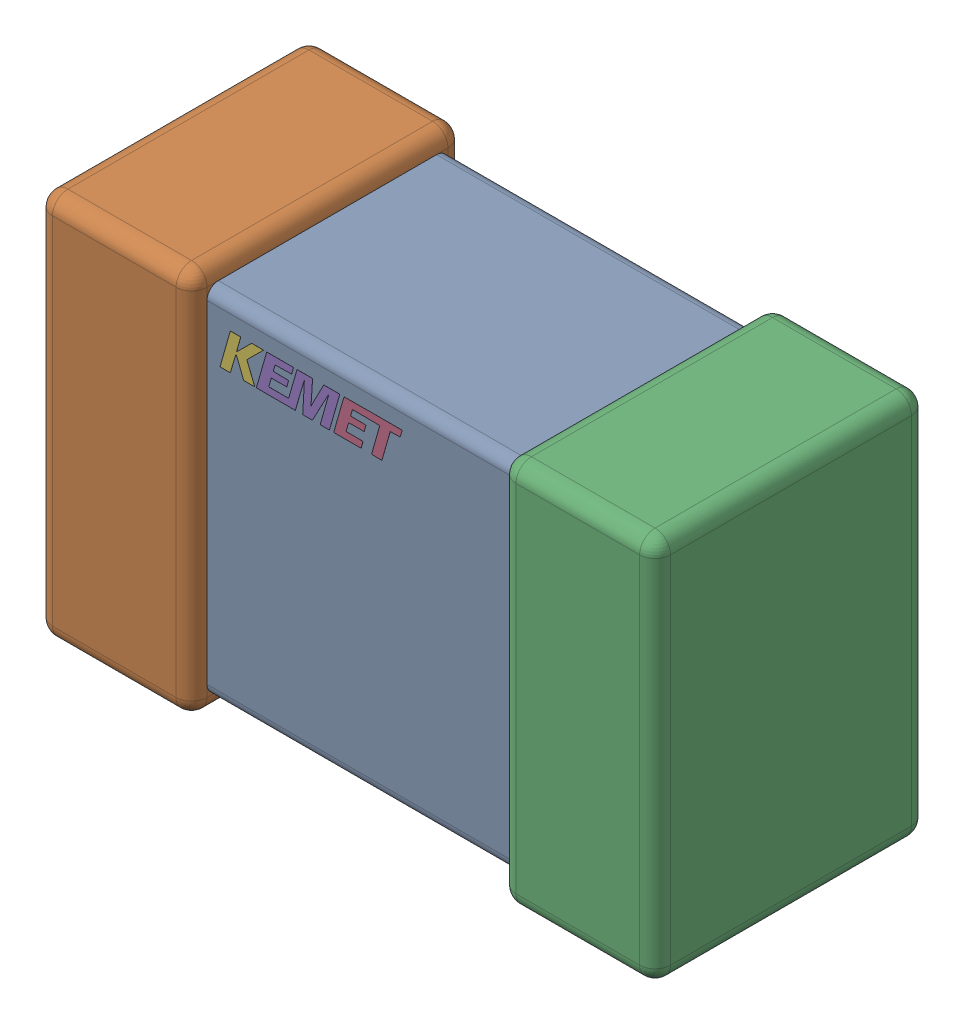
SolidWorks assembly C17.step, configuration Default. Lengths in mm.
Overall size (2 1.25 0.88).
3 component instances, 3 part files, 0 mates.
Components (placement in the parent):
- Cap_KEMET_C0805C472J3HAC_eec.step-1: Cap_KEMET_C0805C472J3HAC_eec.step [Default] at (56.841 45.974 0) size (1 1.15 0.78)
- Cap_KEMET_C0805C472J3HAC_eec-7.step-1: Cap_KEMET_C0805C472J3HAC_eec-7.step [Default] at (56.841 45.974 0) size (2 1.25 0.88)
- Cap_KEMET_C0805C472J3HAC_eec-8.step-1: Cap_KEMET_C0805C472J3HAC_eec-8.step [Default] at (56.841 45.974 0) size (0.59 0.12 0)
